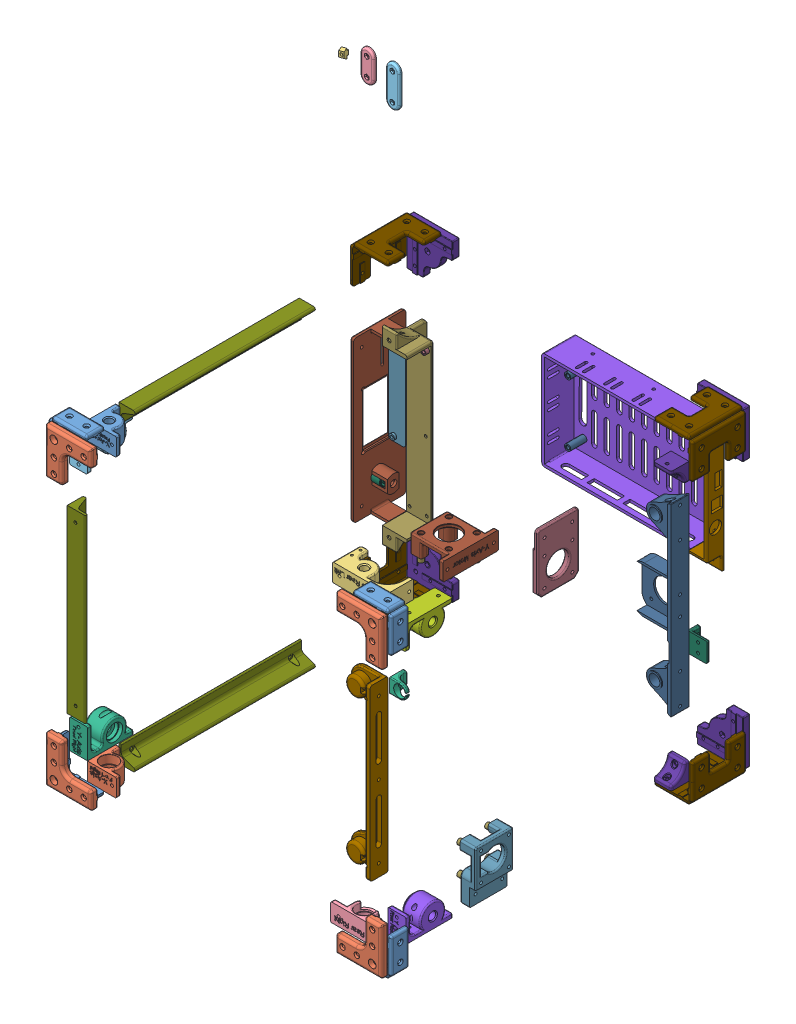
SolidWorks assembly 3D Printed Parts, configuration Default. Lengths in mm.
Overall size (474.29 485.42 420.93).
75 component instances, 35 part files, 0 mates.
Components (placement in the parent):
- Gantry Supports-1: Gantry Supports [Default] at origin size (374.02 348.21 354.88)
  - X-Axis Front Left-1: X-Axis Front Left [Default] at (10.805 -7.42 25) size (32.2 20.01 32.27)
  - X-Axis Front Right-1: X-Axis Front Right [Default] at (15.2086 8.0733 0) size (32.2 20.01 32.27)
  - X-Axis Rear Left-1: X-Axis Rear Left [Default] at (732.39 308.3 0) x (-1 0 0) z (0 0 1) size (61.58 20.01 31.88)
  - X-Axis Rear Right-1: X-Axis Rear Right [Default] at origin size (63.58 20.01 28.78)
  - Y-Axis Front Left-1: Y-Axis Front Left [Default] at origin size (20.04 32.56 51.28)
  - Y-Axis Front Right-1: Y-Axis Front Right [Default] at origin size (20 32.54 51.28)
  - Y-Axis Rear Left-1: Y-Axis Rear Left [Default] at origin size (22.31 26.25 52.04)
  - Y-Axis Rear Right-1: Y-Axis Rear Right [Default] at origin size (22.31 26.25 52.04)
  - Z-Axis Support Top (339mm)-1: Z-Axis Support Top (339mm) [Default] at (-75 10 0) size (36.51 188.6 20)
  - Z-Axis Support Bottom (339mm)-1: Z-Axis Support Bottom (339mm) [Default] at (0.1592 0.1845 0.1206) size (48.55 205.25 20.01)
- Motor Supports-1: Motor Supports [Default] at origin size (70.23 348.36 128.41)
  - Y-Axis Motor Support-1: Y-Axis Motor Support [Default] at origin size (47.03 20.31 61.91)
  - Motor Support Spacer-1: Motor Support Spacer [Default] at origin size (6 7 6)
  - Motor Support Spacer-2: Motor Support Spacer [Default] at (31 0 0) size (6 7 6)
  - Motor Support Spacer-3: Motor Support Spacer [Default] at (0 0 -31) size (6 7 6)
  - Motor Support Spacer-4: Motor Support Spacer [Default] at (31 0 -31) size (6 7 6)
  - Motor Support Spacer-5: Motor Support Spacer [Default] at (535.1952 -15.3872 -302.782) x (0 0 1) z (0 -1 0) size (6 7 6)
  - Motor Support Spacer-6: Motor Support Spacer [Default] at (535.1952 -15.3872 -271.782) x (0 0 1) z (0 -1 0) size (6 7 6)
  - Motor Support Spacer-7: Motor Support Spacer [Default] at (535.1952 -46.3872 -302.782) x (0 0 1) z (0 -1 0) size (6 7 6)
  - Motor Support Spacer-8: Motor Support Spacer [Default] at (535.1952 -46.3872 -271.782) x (0 0 1) z (0 -1 0) size (6 7 6)
  - Extruder Motor Support-1: Extruder Motor Support [Default] at origin size (6.2 66.3 46.3)
  - X-Axis Motor Support v2-1: X-Axis Motor Support v2 [Default] at (0 2 0) size (17.11 60.63 42.1)
- Z-Axis Endstop-1: Z-Axis Endstop [Default] at (1.5 0 0) size (22.66 22.12 12.2)
- Brackets & Base-1: Brackets & Base [Default] at origin size (474.29 485.42 420.93)
  - Rubber Foot-1: Rubber Foot [Default] at (-395.7182 -511.0471 -46.9882) size (24.9 24.9 10.5)
  - Foot Bracket-1: Foot Bracket [Default] at origin size (51.02 51.02 9.01)
  - Sides Bottom Bracket-1: Sides Bottom Bracket [Default] at origin size (5.01 39.15 60.04)
  - Sides Top Bracket-1: Sides Top Bracket [Default] at (0 -308.892 0) size (5.02 39.15 20.04)
  - Top Cap Bracket-1: Top Cap Bracket [Default] at (218.2981 -218.205 1.08) x (0 1 0) z (0 0 -1) size (51.21 51.21 8.43)
  - Post Assembly Nut (HNTFSN5) v1-1: Post Assembly Nut (HNTFSN5) v1 [Default] at (-31.693 289.2047 -199.96) x (0 0 -1) z (-0.965926 -0.258819 0) size (4.7 10 8.89)
  - Floor 20mm Connector-1: Floor 20mm Connector [Default] at (0 0 -199.96) size (15 35 3.2)
  - Floor 30mm Connector-1: Floor 30mm Connector [Default] at (0 0 -199.96) size (15 45 3.2)
  - Bowden Support Bracket-1: Bowden Support Bracket [Default] at origin size (18.8 16 17.01)
  - Sides Top Bracket-2: Sides Top Bracket [Default] at (0 0.0001 0) size (5.02 39.15 20.04)
  - Rubber Foot-2: Rubber Foot [Default] at (755.1521 -613.9231 -46.9882) x (0 1 0) z (0 0 1) size (24.9 24.9 10.5)
  - Foot Bracket-2: Foot Bracket [Default] at (244.105 -218.205 0) x (0 1 0) z (0 0 1) size (51.02 51.02 9.01)
  - Foot Bracket-3: Foot Bracket [Default] at (218.305 218.105 0) x (0 -1 0) z (0 0 1) size (51.02 51.02 9.01)
  - Rubber Foot-3: Rubber Foot [Default] at (-292.7421 613.8232 -46.9882) x (0 -1 0) z (0 0 1) size (24.9 24.9 10.5)
  - Foot Bracket-4: Foot Bracket [Default] at (462.41 -0.1 0) x (-1 0 0) z (0 0 1) size (51.02 51.02 9.01)
  - Rubber Foot-4: Rubber Foot [Default] at (858.1282 510.9471 -46.9882) x (-1 0 0) z (0 0 1) size (24.9 24.9 10.5)
  - Top Cap Bracket-2: Top Cap Bracket [Default] at (0 0 1.08) x (1 0 0) z (0 0 -1) size (51.21 51.21 8.43)
  - Top Cap Bracket-3: Top Cap Bracket [Default] at (462.41 0.1 1.08) x (-1 0 0) z (0 0 -1) size (51.21 51.21 8.43)
  - Top Cap Bracket-4: Top Cap Bracket [Default] at (244.105 218.205 1.08) x (0 -1 0) z (0 0 -1) size (51.21 51.21 8.43)
  - Sides Bottom Bracket-2: Sides Bottom Bracket [Default] at (0 0 -323.92) x (1 0 0) z (0 0 -1) size (5.01 39.15 60.04)
  - Sides Bottom Bracket-3: Sides Bottom Bracket [Default] at (462.41 0 -323.92) x (-1 0 0) z (0 0 -1) size (5.01 39.15 60.04)
  - Sides Top Bracket-3: Sides Top Bracket [Default] at (462.41 -0.0001 0) x (-1 0 0) z (0 0 1) size (5.02 39.15 20.04)
  - Sides Bottom Bracket-4: Sides Bottom Bracket [Default] at (462.41 0 0) x (-1 0 0) z (0 0 1) size (5.01 39.15 60.04)
  - Sides Top Bracket-4: Sides Top Bracket [Default] at (462.41 308.892 0) x (-1 0 0) z (0 0 1) size (5.02 39.15 20.04)
  - Sides Top Bracket-5: Sides Top Bracket [Default] at (-90.687 218.305 0) x (0 -1 0) z (0 0 1) size (5.02 39.15 20.04)
  - Sides Top Bracket-6: Sides Top Bracket [Default] at (553.1027 218.305 386.08) x (0 -1 0) z (0 0 -1) size (5.02 39.15 20.04)
  - Sides Bottom Bracket-5: Sides Bottom Bracket [Default] at (244.205 218.305 -323.92) x (0 -1 0) z (0 0 -1) size (5.01 39.15 60.04)
  - Sides Bottom Bracket-6: Sides Bottom Bracket [Default] at (218.205 218.305 0) x (0 -1 0) z (0 0 1) size (5.01 39.15 60.04)
  - Sides Bottom Bracket-7: Sides Bottom Bracket [Default] at (244.205 -218.105 0) x (0 1 0) z (0 0 1) size (5.01 39.15 60.04)
  - Sides Bottom Bracket-8: Sides Bottom Bracket [Default] at (218.205 -218.105 -323.92) x (0 1 0) z (0 0 -1) size (5.01 39.15 60.04)
  - Sides Top Bracket-7: Sides Top Bracket [Default] at (-90.6927 -218.105 386.08) x (0 1 0) z (0 0 -1) size (5.02 39.15 20.04)
  - Sides Top Bracket-8: Sides Top Bracket [Default] at (553.097 -218.105 0) x (0 1 0) z (0 0 1) size (5.02 39.15 20.04)
- X-Axis Endstop-1: X-Axis Endstop [Default] at (-0.1138 -4.9987 0) size (28.37 20.12 19.24)
- Mainboard-1: Mainboard [Default] at origin size (187.25 124.27 38.91)
  - Mainboard Enclosure-1: Mainboard Enclosure [Default] at origin size (166.96 124.27 35.75)
  - Mainboard Face Plate-1: Mainboard Face Plate [Default] at (-0.765 0 0) size (21.06 124.26 19.76)
  - Mainboard Spacer-1: Mainboard Spacer [Default] at origin size (7 7 17.97)
  - Mainboard Spacer-2: Mainboard Spacer [Default] at (0 -69 0) size (7 7 17.97)
- OLED Display-1: OLED Display [Default] at origin size (62.75 211.6 59)
  - OLED Display Face Plate-1: OLED Display Face Plate [Default] at (-2.7 0 0) size (23.8 178 58)
  - OLED Electronics Support-1: OLED Electronics Support [Default] at origin size (27.25 211.6 47.43)
  - OLED Electronics Spacer-1: OLED Electronics Spacer [Default] at origin size (6.2 6.2 4.05)
  - OLED Display Front Support-1: OLED Display Front Support [Default] at origin size (18.76 110 4.1)
  - OLED Knob v1-1: OLED Knob v1 [Default] at (-50 225 -200) x (0 -1 0) z (1 0 0) size (32.96 32.98 25.23)
    - Fillet (1)-1: Fillet (1) [Default] at (284.384 -40.195 77.273) x (-1 0 0) z (0 0 1) size (32.96 32.98 25.23)
- LED Mount-1: LED Mount [Default] at (-0.2292 0 -2.4895) size (20 200.5 17.84)
- LED Mount-2: LED Mount [Default] at (252.2345 218.4342 64.6296) x (0 -1 0) z (-1 0 0) size (20 200.5 17.84)
- LED Mount-3: LED Mount [Default] at (252.2345 -218.4342 30.9127) x (0 1 0) z (-1 0 0) size (20 200.5 17.84)
- Z-Axis Bottom Brace-1: Z-Axis Bottom Brace [Default] at (0 0 -200) size (20.51 20 20.28)
- Z-Axis Bottom Brace-2: Z-Axis Bottom Brace [Default] at (0 -222.04 22.0408) x (1 0 0) z (0 1 0) size (20.51 20 20.28)
